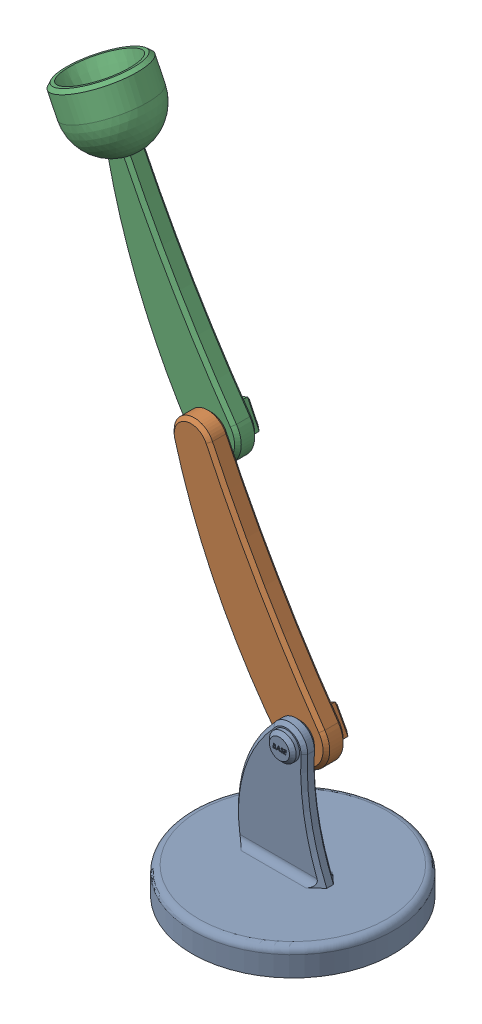
SolidWorks assembly Two_Link_Robotic_Arm_Assembly, configuration Default. Lengths in mm.
Overall size (273.57 448.63 150).
3 component instances, 3 part files, 4 mates.
Components (placement in the parent):
- Part_0_Link_0-1: Part_0_Link_0 [Default] at (-268.419 0 -146.2339) size (150 113.53 150)
- Part_1_Arm_1-1: Part_1_Arm_1 [Default] at (-308.9003 174.7413 -158.7339) x (-0.47625 0.87931 0) z (0 0 -1) size (205 46.12 35)
- Part_2_Arm_2-1: Part_2_Arm_2 [Default] at (-386.6159 325.8934 -173.7339) x (-0.438051 0.89895 0) z (0 0 -1) size (226.91 60 60)
Mates (geometry in assembly coordinates):
- Coincident2: coincident anti-aligned: plane of Part_0_Link_0-1 through (-206.4553 39.4547 -151.2339) normal (0 0 -1); plane of Part_1_Arm_1-1 through (-308.9003 174.7413 -151.2339) normal (0 0 1)
- Concentric1: concentric aligned: cylinder of Part_0_Link_0-1 through (-268.419 100 -141.2339) axis (0 0 -1) radius 5; cylinder of Part_1_Arm_1-1 through (-268.419 100 -141.2339) axis (0 0 -1) radius 5
- Coincident4: coincident anti-aligned: plane of Part_1_Arm_1-1 through (-308.9003 174.7413 -166.2339) normal (0 0 -1); plane of Part_2_Arm_2-1 through (-386.6159 325.8934 -166.2339) normal (0 0 1)
- Concentric2: concentric aligned: cylinder of Part_1_Arm_1-1 through (-349.3815 249.4827 -156.2339) axis (0 0 -1) radius 5; cylinder of Part_2_Arm_2-1 through (-349.3815 249.4827 -156.2339) axis (0 0 -1) radius 5
